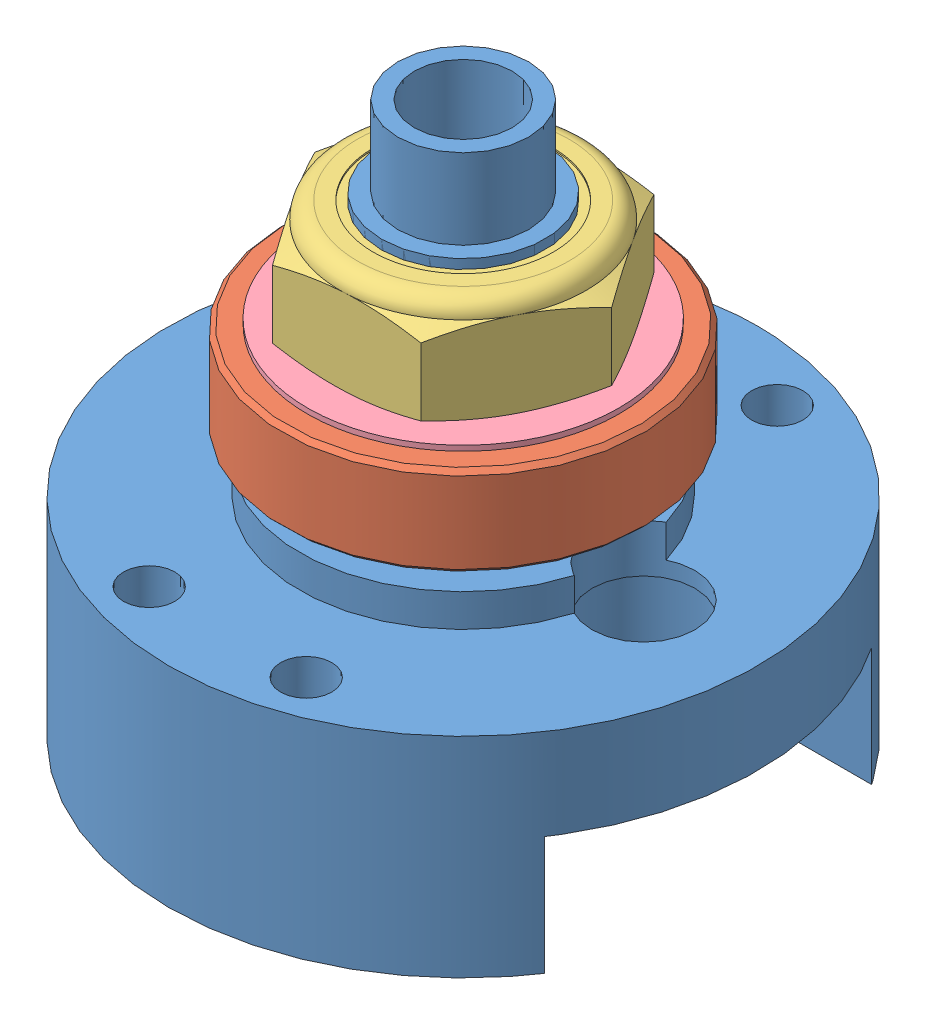
SolidWorks assembly Shaft Assembly Test, configuration Default. Lengths in mm.
Overall size (57.15 53.65 57.15).
4 component instances, 4 part files, 6 mates.
Components (placement in the parent):
- Shaft_Carrier_Combined_V2-1: Shaft_Carrier_Combined_V2 [Default] at (4.6642 1.3555 -7.8075) size (57.15 53.65 57.15)
- Bearing-.625in-1: Bearing-.625in [3760T16] at (4.6642 11.4361 -7.8075) x (-0.796088 0 0.60518) z (0 1 0) size (34.92 34.92 8.73)
- Locknut-.625in-1: Locknut-.625in [94945A230] at (4.6642 16.3097 -7.8075) x (0.889414 0 0.457103) z (-0.457103 0 0.889414) size (23.81 10.38 27.5)
- Washer-.625in.-1: Washer-.625in. [95229A600] at (4.6642 16.3097 -7.8075) x (0.996219 0 0.086882) z (0 1 0) size (30.23 30.23 0.51)
Mates (geometry in assembly coordinates):
- Concentric1: concentric anti-aligned: cylinder of Shaft_Carrier_Combined_V2-1 through (4.6642 26.9142 -7.8075) axis (0 -1 0) radius 7.9375; cylinder of Bearing-.625in-1 through (4.6642 15.8017 -7.8075) axis (0 1 0) radius 7.9375
- Coincident1: coincident anti-aligned: plane of Shaft_Carrier_Combined_V2-1 through (4.6642 7.0705 -7.8075) normal (0 1 0); plane of Bearing-.625in-1 through (9.732 7.0705 -1.141) normal (0 -1 0)
- Concentric2: concentric anti-aligned: cylinder of Shaft_Carrier_Combined_V2-1 through (4.6642 26.9142 -7.8075) axis (0 -1 0) radius 7.9375; cylinder of Washer-.625in.-1 through (4.6642 15.8017 -7.8075) axis (0 1 0) radius 8.128
- Coincident2: coincident anti-aligned: plane of Bearing-.625in-1 through (11.6532 15.8017 1.3863) normal (0 1 0); plane of Washer-.625in.-1 through (4.6642 15.8017 -7.8075) normal (0 -1 0)
- Coincident3: coincident anti-aligned: plane of Locknut-.625in-1 through (3.5011 16.3097 -31.5916) normal (0 -1 0); plane of Washer-.625in.-1 through (4.6642 16.3097 -7.8075) normal (0 1 0)
- Concentric3: concentric aligned: cylinder of Shaft_Carrier_Combined_V2-1 through (4.6642 26.9142 -7.8075) axis (0 -1 0) radius 7.9375; circle of Locknut-.625in-1
